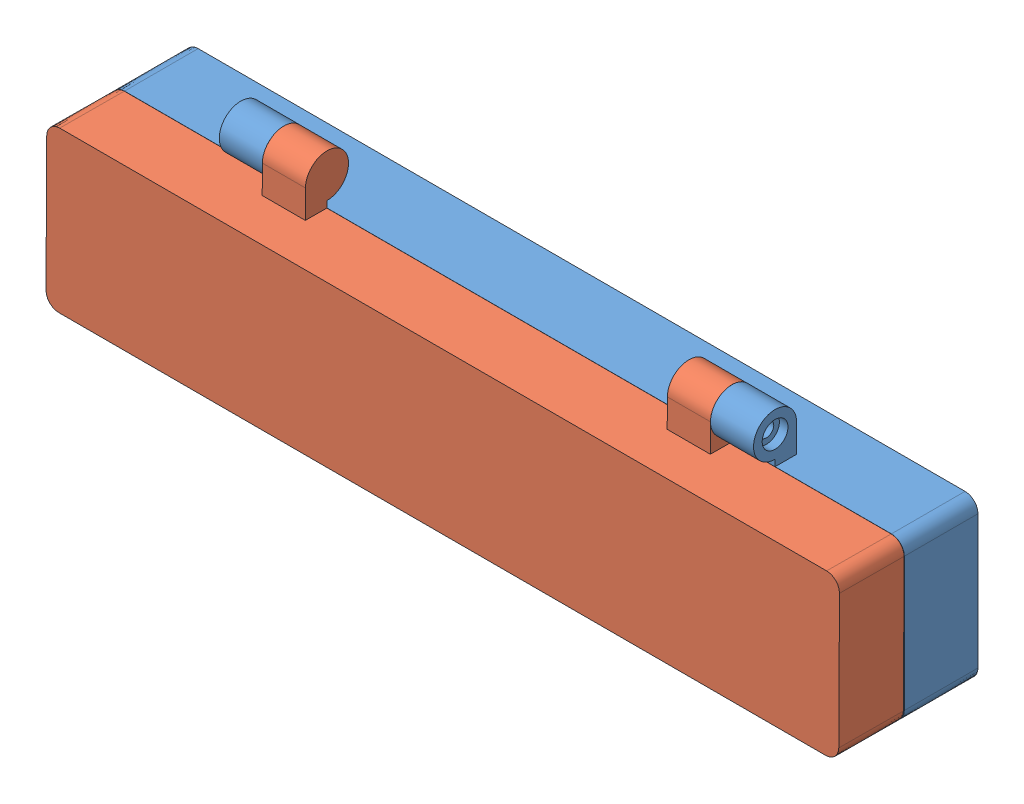
SolidWorks assembly Caja_Completa, configuration Predeterminado. Lengths in mm.
Overall size (184 54.26 32.35).
2 component instances, 2 part files, 2 mates.
Components (placement in the parent):
- Base-1: Base [Predeterminado] at (86.183 -21.115 172.95) size (184 54.18 22.1)
- Tapa-2: Tapa [Predeterminado] at (-97.817 -21.0329 205.2859) x (-1 0 0) z (0 -0.005428 -0.999985) size (184 52 20)
Mates (geometry in assembly coordinates):
- Coincidente1: coincident: plane of assembly; plane of assembly; plane of Base-1 through (46.183 22.385 190.05) normal (-1 0 0); plane of Tapa-2 through (46.183 22.385 190.05) normal (1 0 0)
- Concéntrica1: concentric: cylinder of assembly; cylinder of assembly; cylinder of Base-1 through (46.183 22.385 190.05) axis (1 0 0) radius 1.7; cylinder of Tapa-2 through (41.183 22.385 190.05) axis (1 0 0) radius 1.7
